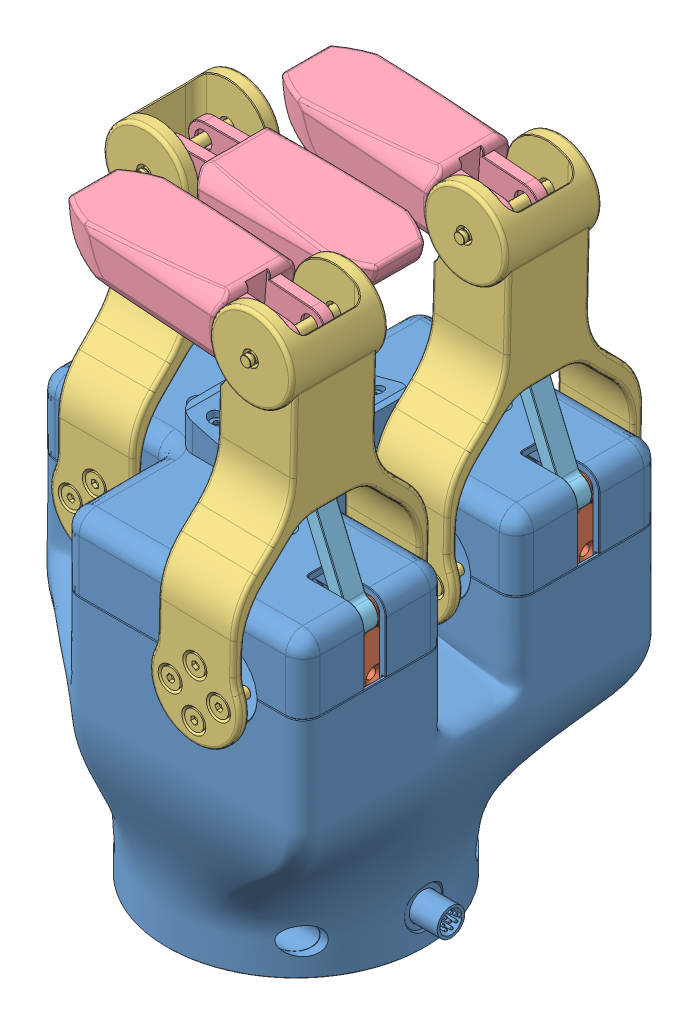
SolidWorks assembly CTTFG60.00-P_三指机械手(仿形指)-20220719-00, configuration 默认. Lengths in mm.
Overall size (109.11 180.03 119).
16 component instances, 5 part files, 11 mates.
Components (placement in the parent):
- CTTFG60.00-P_三指机械手(仿形指)-20220719-01-1: CTTFG60.00-P_三指机械手(仿形指)-20220719-01 [默认] at origin size (109.11 119.25 104.61)
- CTTFG60.01.02_单指组件-20220719-1: CTTFG60.01.02_单指组件-20220719 [默认] at (44.25 26.625 31) x (0 0 1) z (-1 0 0) size (57 149.78 109.56) (flexible)
  - CTTFG60.01.02.02_连接杆固定铰座组件-20220719-1: CTTFG60.01.02.02_连接杆固定铰座组件-20220719 [默认] at (0 0 -2) x (-1 0 0) z (0 0 -1) size (20 53.25 8)
  - CTTFG60.01.02.03_驱动指组件-20220719-1: CTTFG60.01.02.03_驱动指组件-20220719 [默认] at (0 57.112 13.1495) x (0 -0.023666 -0.99972) z (1 0 0) size (26 102.75 57)
  - CTTFG60.01.02.04_从动指组件-20220719-1: CTTFG60.01.02.04_从动指组件-20220719 [默认] at (0 87.6922 16.8612) x (0 -0.076592 -0.997063) z (1 0 0) size (64.97 18.39 27)
  - CTTFG60.01.02.05_连接杆组件-20220719-1: CTTFG60.01.02.05_连接杆组件-20220719 [默认] at (0 53.8043 8.548) x (1 0 0) z (0 -0.9215 -0.388379) size (6 8 71.33)
- CTTFG60.01.02_单指组件-20220719-2: CTTFG60.01.02_单指组件-20220719 [默认] at (44.25 26.625 -31) x (0 0 1) z (-1 0 0) size (57 149.78 109.56) (flexible)
  - CTTFG60.01.02.02_连接杆固定铰座组件-20220719-1: CTTFG60.01.02.02_连接杆固定铰座组件-20220719 [默认] at (0 0 -2) x (-1 0 0) z (0 0 -1) size (20 53.25 8)
  - CTTFG60.01.02.03_驱动指组件-20220719-1: CTTFG60.01.02.03_驱动指组件-20220719 [默认] at (0 57.112 13.1495) x (0 -0.023666 -0.99972) z (1 0 0) size (26 102.75 57)
  - CTTFG60.01.02.04_从动指组件-20220719-1: CTTFG60.01.02.04_从动指组件-20220719 [默认] at (0 87.6922 16.8612) x (0 -0.076592 -0.997063) z (1 0 0) size (64.97 18.39 27)
  - CTTFG60.01.02.05_连接杆组件-20220719-1: CTTFG60.01.02.05_连接杆组件-20220719 [默认] at (0 53.8043 8.548) x (1 0 0) z (0 -0.9215 -0.388379) size (6 8 71.33)
- CTTFG60.01.02_单指组件-20220719-3: CTTFG60.01.02_单指组件-20220719 [默认] at (-44.25 26.625 0) x (0 0 -1) z (1 0 0) size (57 149.78 109.56) (flexible)
  - CTTFG60.01.02.02_连接杆固定铰座组件-20220719-1: CTTFG60.01.02.02_连接杆固定铰座组件-20220719 [默认] at (0 0 -2) x (-1 0 0) z (0 0 -1) size (20 53.25 8)
  - CTTFG60.01.02.03_驱动指组件-20220719-1: CTTFG60.01.02.03_驱动指组件-20220719 [默认] at (0 57.125 14.25) x (0 0 -1) z (1 0 0) size (26 102.75 57)
  - CTTFG60.01.02.04_从动指组件-20220719-1: CTTFG60.01.02.04_从动指组件-20220719 [默认] at (0 87.3737 18.6372) x (0 0.000302 -1) z (1 0 0) size (64.97 18.39 27)
  - CTTFG60.01.02.05_连接杆组件-20220719-1: CTTFG60.01.02.05_连接杆组件-20220719 [默认] at (0 53.4988 9.2491) x (1 0 0) z (0 -0.911852 -0.410519) size (6 8 71.33)
Mates (geometry in assembly coordinates):
- 重合1: coincident aligned: plane of CTTFG60.00-P_三指机械手(仿形指)-20220719-01-1 through (0 0 0) normal (0 0 1); plane of assembly through (0 0 0) normal (0 0 1)
- 重合2: coincident aligned: plane of CTTFG60.00-P_三指机械手(仿形指)-20220719-01-1 through (0 0 0) normal (1 0 0); plane of assembly through (0 0 0) normal (1 0 0)
- 重合3: coincident aligned: plane of CTTFG60.00-P_三指机械手(仿形指)-20220719-01-1 through (0 0 0) normal (0 1 0); plane of assembly through (0 0 0) normal (0 1 0)
- 距离1: distance = 4.5 mm anti-aligned: plane of CTTFG60.01.02_单指组件-20220719-1/CTTFG60.01.02.03_驱动指组件-20220719-1 through (21.8107 44.5941 56.5) normal (0 0 -1); plane of CTTFG60.00-P_三指机械手(仿形指)-20220719-01-1 through (-54 57.5 52) normal (0 0 1)
- 距离6: distance = 12.25 mm aligned: plane of CTTFG60.00-P_三指机械手(仿形指)-20220719-01-1 through (0 57.5 0) normal (0 1 0); plane of CTTFG60.01.02_单指组件-20220719-1/CTTFG60.01.02.02_连接杆固定铰座组件-20220719-1 through (44 45.25 34.1) normal (0 1 0)
- 距离7: distance = 5.75 mm aligned: plane of CTTFG60.01.02_单指组件-20220719-1/CTTFG60.01.02.02_连接杆固定铰座组件-20220719-1 through (48.25 26.625 31) normal (1 0 0); plane of CTTFG60.00-P_三指机械手(仿形指)-20220719-01-1 through (54 57.5 -52) normal (1 0 0)
- 平行5: parallel aligned: plane of CTTFG60.01.02_单指组件-20220719-1/CTTFG60.01.02.03_驱动指组件-20220719-1 through (100.2803 99.1425 59.5) normal (0.74448 -0.667645 0); plane of ? through (100.2803 99.1425 -2.5) normal (0.74448 -0.667645 0)
- 重合14: coincident aligned: plane of CTTFG60.01.02_单指组件-20220719-1/CTTFG60.01.02.02_连接杆固定铰座组件-20220719-1 through (44 45.25 34.1) normal (0 1 0); plane of CTTFG60.01.02_单指组件-20220719-3/CTTFG60.01.02.02_连接杆固定铰座组件-20220719-1 through (-44 45.25 -3.1) normal (0 1 0)
- 距离8: distance = 4.5 mm anti-aligned: plane of ? through (-21.8107 44.5941 25.5) normal (0 0 -1); plane of CTTFG60.00-P_三指机械手(仿形指)-20220719-01-1 through (-54 55.5 21) normal (0 0 1)
- 距离9: distance = 5.75 mm aligned: plane of CTTFG60.00-P_三指机械手(仿形指)-20220719-01-1 through (-54 57.5 -52) normal (-1 0 0); plane of CTTFG60.01.02_单指组件-20220719-3/CTTFG60.01.02.02_连接杆固定铰座组件-20220719-1 through (-48.25 26.625 0) normal (-1 0 0)
- 对称1: symmetric aligned: plane of CTTFG60.00-P_三指机械手(仿形指)-20220719-01-1 through (0 0 0) normal (1 0 0); plane of ?; plane of ?
